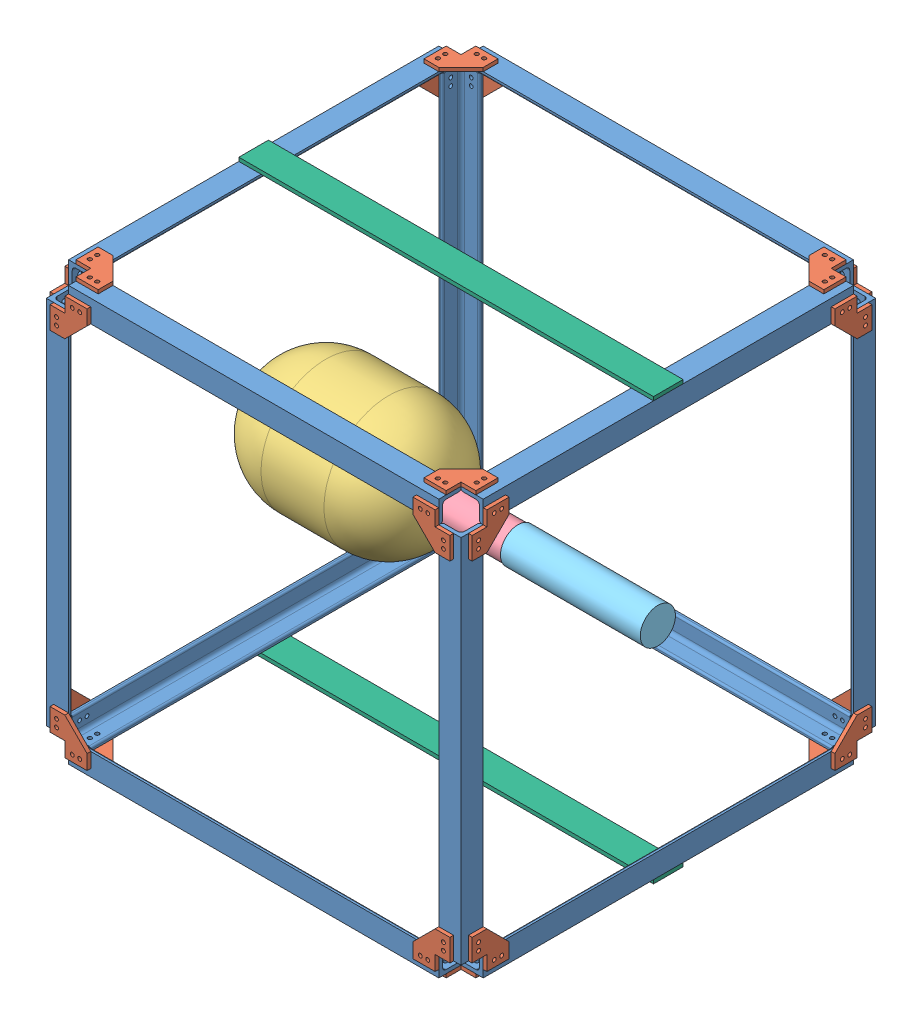
SolidWorks assembly 14 inch with Tank and mounting, configuration Default. Lengths in mm.
Overall size (361.95 361.95 361.95).
45 component instances, 8 part files, 18 mates.
Components (placement in the parent):
- Outer struct 14 in side length-1: Outer struct 14 in side length [Default] at origin size (361.95 361.95 361.95)
  - WIP 14 inch .75 L rod-1: WIP 14 inch .75 L rod [8982K281] at (-9.525 9.525 0) size (19.05 19.05 317.5)
  - WIP bracket for .75 L bar-1: WIP bracket for .75 L bar [Default] at (-44.45 -3.175 -171.45) size (31.75 3.17 31.75)
  - WIP 14 inch .75 L rod-2: WIP 14 inch .75 L rod [8982K281] at (-177.8 9.525 -168.275) x (0 0 -1) z (1 0 0) size (19.05 19.05 317.5)
  - WIP 14 inch .75 L rod-3: WIP 14 inch .75 L rod [8982K281] at (-9.525 177.8 -168.275) x (1 0 0) z (0 -1 0) size (19.05 19.05 317.5)
  - WIP bracket for .75 L bar-2: WIP bracket for .75 L bar [Default] at (0 44.45 -171.45) x (0 -1 0) z (0 0 1) size (31.75 3.17 31.75)
  - WIP bracket for .75 L bar-3: WIP bracket for .75 L bar [Default] at (-44.45 6.35 -177.8) x (1 0 0) z (0 1 0) size (31.75 3.17 31.75)
  - WIP bracket for .75 L bar-4: WIP bracket for .75 L bar [Default] at (-311.15 349.25 -177.8) x (-1 0 0) z (0 -1 0) size (31.75 3.17 31.75)
  - WIP bracket for .75 L bar-5: WIP bracket for .75 L bar [Default] at (-355.6 311.15 -171.45) x (0 1 0) z (0 0 1) size (31.75 3.17 31.75)
  - WIP bracket for .75 L bar-6: WIP bracket for .75 L bar [Default] at (-311.15 358.775 -171.45) x (-1 0 0) z (0 0 1) size (31.75 3.17 31.75)
  - WIP 14 inch .75 L rod-4: WIP 14 inch .75 L rod [8982K281] at (-177.8 346.075 -168.275) x (0 0 -1) z (-1 0 0) size (19.05 19.05 317.5)
  - WIP 14 inch .75 L rod-5: WIP 14 inch .75 L rod [8982K281] at (-346.075 346.075 0) x (-1 0 0) z (0 0 1) size (19.05 19.05 317.5)
  - WIP 14 inch .75 L rod-6: WIP 14 inch .75 L rod [8982K281] at (-346.075 177.8 -168.275) x (-1 0 0) z (0 1 0) size (19.05 19.05 317.5)
  - WIP bracket for .75 L bar-8: WIP bracket for .75 L bar [Default] at (-6.35 311.15 -177.8) x (0 1 0) z (-1 0 0) size (31.75 3.17 31.75)
  - WIP bracket for .75 L bar-9: WIP bracket for .75 L bar [Default] at (-349.25 44.45 -177.8) x (0 -1 0) z (1 0 0) size (31.75 3.17 31.75)
  - WIP bracket for .75 L bar-11: WIP bracket for .75 L bar [Default] at (-6.35 355.6 133.35) x (0 0 1) z (-1 0 0) size (31.75 3.17 31.75)
  - WIP bracket for .75 L bar-12: WIP bracket for .75 L bar [Default] at (-44.45 349.25 177.8) x (1 0 0) z (0 -1 0) size (31.75 3.17 31.75)
  - WIP 14 inch .75 L rod-7: WIP 14 inch .75 L rod [8982K281] at (-177.8 346.075 168.275) x (0 0 1) z (1 0 0) size (19.05 19.05 317.5)
  - WIP 14 inch .75 L rod-8: WIP 14 inch .75 L rod [8982K281] at (-9.525 346.075 0) x (0 1 0) z (0 0 1) size (19.05 19.05 317.5)
  - WIP bracket for .75 L bar-13: WIP bracket for .75 L bar [Default] at (3.175 349.25 133.35) x (0 0 1) z (0 -1 0) size (31.75 3.17 31.75)
  - WIP 14 inch .75 L rod-9: WIP 14 inch .75 L rod [8982K281] at (-9.525 177.8 168.275) x (0 0 1) z (0 -1 0) size (19.05 19.05 317.5)
  - WIP bracket for .75 L bar-14: WIP bracket for .75 L bar [Default] at (3.175 311.15 -171.45) x (0 1 0) z (0 0 1) size (31.75 3.17 31.75)
  - WIP bracket for .75 L bar-15: WIP bracket for .75 L bar [Default] at (-349.25 358.775 133.35) x (0 0 1) z (1 0 0) size (31.75 3.17 31.75)
  - WIP bracket for .75 L bar-16: WIP bracket for .75 L bar [Default] at (-44.45 355.6 -171.45) size (31.75 3.17 31.75)
  - WIP bracket for .75 L bar-17: WIP bracket for .75 L bar [Default] at (-6.35 -3.175 133.35) x (0 0 1) z (-1 0 0) size (31.75 3.17 31.75)
  - WIP bracket for .75 L bar-18: WIP bracket for .75 L bar [Default] at (3.175 44.45 171.45) x (0 -1 0) z (0 0 -1) size (31.75 3.17 31.75)
  - WIP bracket for .75 L bar-19: WIP bracket for .75 L bar [Default] at (-349.25 311.15 177.8) x (0 1 0) z (1 0 0) size (31.75 3.17 31.75)
  - WIP bracket for .75 L bar-20: WIP bracket for .75 L bar [Default] at (-355.6 349.25 133.35) x (0 0 1) z (0 -1 0) size (31.75 3.17 31.75)
  - WIP bracket for .75 L bar-21: WIP bracket for .75 L bar [Default] at (-355.6 44.45 171.45) x (0 -1 0) z (0 0 -1) size (31.75 3.17 31.75)
  - WIP 14 inch .75 L rod-11: WIP 14 inch .75 L rod [8982K281] at (-346.075 177.8 168.275) x (-1 0 0) z (0 -1 0) size (19.05 19.05 317.5)
  - WIP bracket for .75 L bar-22: WIP bracket for .75 L bar [Default] at (-311.15 6.35 177.8) x (-1 0 0) z (0 1 0) size (31.75 3.17 31.75)
  - WIP 14 inch .75 L rod-12: WIP 14 inch .75 L rod [8982K281] at (-177.8 9.525 168.275) x (0 0 1) z (-1 0 0) size (19.05 19.05 317.5)
  - WIP bracket for .75 L bar-23: WIP bracket for .75 L bar [Default] at (-311.15 -3.175 171.45) x (-1 0 0) z (0 0 -1) size (31.75 3.17 31.75)
  - WIP 14 inch .75 L rod-13: WIP 14 inch .75 L rod [8982K281] at (-346.075 9.525 0) x (-1 0 0) z (0 0 -1) size (19.05 19.05 317.5)
  - WIP bracket for .75 L bar-24: WIP bracket for .75 L bar [Default] at (-355.6 6.35 -133.35) x (0 0 -1) z (0 1 0) size (31.75 3.17 31.75)
  - WIP bracket for .75 L bar-25: WIP bracket for .75 L bar [Default] at (-349.25 -3.175 -133.35) x (0 0 -1) z (1 0 0) size (31.75 3.17 31.75)
  - WIP bracket for .75 L bar-26: WIP bracket for .75 L bar [Default] at (-6.35 44.45 177.8) x (0 -1 0) z (-1 0 0) size (31.75 3.17 31.75)
- LoFi Tank+Reg-1: LoFi Tank+Reg [Default] at (-266.7 177.8 0) x (0 -0.004235 -0.999991) z (-1 0 0) size (111.12 111.12 340.27)
  - LoFi Tank-1: LoFi Tank [Default] at origin size (111.12 111.12 163.23)
  - LoFi Reg 1-1: LoFi Reg 1 [Default] at (0 0 -80.6816) x (-0.38598 0.922507 0) z (-0.922507 -0.38598 0) size (28.57 57.15 28.57)
  - LoFi Reg 2-1: LoFi Reg 2 [Default] at (0 0 -137.8316) x (-0.99247 0.12249 0) z (-0.12249 -0.99247 0) size (30.16 119.89 30.16)
- Part2^14 inch with Tank and mounting-1: Part2^14 inch with Tank and mounting [Default] at origin (virtual)
- Part3^14 inch with Tank and mounting-1: Part3^14 inch with Tank and mounting [Default] at (-177.8 355.6 168.275) x (0 0 -1) z (0 1 0) (virtual)
- Tank Bar-2: Tank Bar [Default] at (-304.5647 -3.175 8.9819) size (355.6 3.17 25.4)
- Tank Bar-3: Tank Bar [Default] at (-304.5647 355.6 8.9819) size (355.6 3.17 25.4)
Mates (geometry in assembly coordinates):
- Coincident3: coordinate: point of Outer struct 14 in side length-1
- Perpendicular4: perpendicular: line of LoFi Tank+Reg-1 through (17.6867 177.8 0) axis (-1 0 0)
- Tangent5: tangent aligned: sphere of LoFi Tank+Reg-1/LoFi Tank-1
- Distance3: distance = 177.8 mm: line of LoFi Tank+Reg-1 through (17.6867 177.8 0) axis (-1 0 0); plane of Outer struct 14 in side length-1/WIP 14 inch .75 L rod-2 through (-19.05 0 -158.75) normal (0 -1 0)
- Distance4: distance = 177.8 mm: plane of Outer struct 14 in side length-1/WIP 14 inch .75 L rod-3 through (-19.05 19.05 -177.8) normal (0 0 -1); line of LoFi Tank+Reg-1 through (17.6867 177.8 0) axis (-1 0 0)
- InPlace1: in place: plane of Outer struct 14 in side length-1/WIP 14 inch .75 L rod-7 through (-19.05 355.6 158.75) normal (0 1 0); plane of ? through (0 355.6 0) normal (0 1 0); moOrthogonalPlaneRef_w of Outer struct 14 in side length-1/WIP 14 inch .75 L rod-7 through (-19.05 355.6 158.75) normal (0 1 0); plane of ? through (0 355.6 0) normal (0 0 -1); plane of Outer struct 14 in side length-1/WIP 14 inch .75 L rod-7 through (-19.05 355.6 158.75) normal (0 1 0); plane of ? through (0 355.6 0) normal (1 0 0); plane of Outer struct 14 in side length-1/WIP 14 inch .75 L rod-7 through (-19.05 355.6 158.75) normal (0 1 0); unknown of Part3^14 inch with Tank and mounting-1
- Coincident4: coincident aligned: plane of Outer struct 14 in side length-1/WIP 14 inch .75 L rod-7; plane of Part3^14 inch with Tank and mounting-1
- Coincident5: coincident aligned: moOrthogonalPlaneRef_w of Outer struct 14 in side length-1/WIP 14 inch .75 L rod-7 through (-177.8 355.6 168.275) normal (-1 0 0); plane of Part3^14 inch with Tank and mounting-1 through (-177.8 355.6 168.275) normal (-1 0 0)
- Coincident6: coincident anti-aligned: moOrthogonalPlaneRef_w of Outer struct 14 in side length-1/WIP 14 inch .75 L rod-7 through (-177.8 355.6 168.275) normal (0 0 1); plane of Part3^14 inch with Tank and mounting-1 through (-177.8 355.6 168.275) normal (0 0 -1)
- Coincident8: coincident aligned: plane of Outer struct 14 in side length-1/WIP 14 inch .75 L rod-5 through (-355.6 355.6 158.75) normal (-1 0 0); plane of Tank Bar-3 through (-355.6 358.775 -12.6695) normal (-1 0 0)
- Coincident9: coincident aligned: plane of Outer struct 14 in side length-1/WIP 14 inch .75 L rod-8 through (0 336.55 158.75) normal (1 0 0); plane of Tank Bar-3 through (0 358.775 -12.6695) normal (1 0 0)
- Coincident10: coincident anti-aligned: plane of Outer struct 14 in side length-1/WIP 14 inch .75 L rod-8 through (0 355.6 158.75) normal (0 1 0); plane of Tank Bar-3 through (-304.5647 355.6 8.9819) normal (0 -1 0)
- Parallel3: parallel anti-aligned: plane of Outer struct 14 in side length-1/WIP 14 inch .75 L rod-1 through (-19.05 0 158.75) normal (0 -1 0); plane of Tank Bar-2 through (-304.5647 0 8.9819) normal (0 1 0)
- Coincident14: coincident aligned: plane of Outer struct 14 in side length-1/WIP 14 inch .75 L rod-1 through (0 0 158.75) normal (1 0 0); plane of Tank Bar-2 through (0 0 -12.6695) normal (1 0 0)
- Coincident15: coincident aligned: plane of Outer struct 14 in side length-1/WIP 14 inch .75 L rod-13 through (-355.6 0 -158.75) normal (-1 0 0); plane of Tank Bar-2 through (-355.6 0 -12.6695) normal (-1 0 0)
- Coincident16: coincident anti-aligned: plane of Outer struct 14 in side length-1/WIP 14 inch .75 L rod-1 through (-19.05 0 158.75) normal (0 -1 0); plane of Tank Bar-2 through (-304.5647 0 8.9819) normal (0 1 0)
- Distance9: distance = 165.1 mm: line of Tank Bar-2 through (-355.6 -3.175 12.7305) axis (1 0 0); line of Outer struct 14 in side length-1/WIP 14 inch .75 L rod-12 through (-336.55 0 177.8) axis (1 0 0)
- Distance10: distance = 165.1 mm: line of Tank Bar-3 through (-355.6 358.775 12.7305) axis (1 0 0); line of Outer struct 14 in side length-1/WIP 14 inch .75 L rod-7 through (-19.05 355.6 177.8) axis (-1 0 0)
